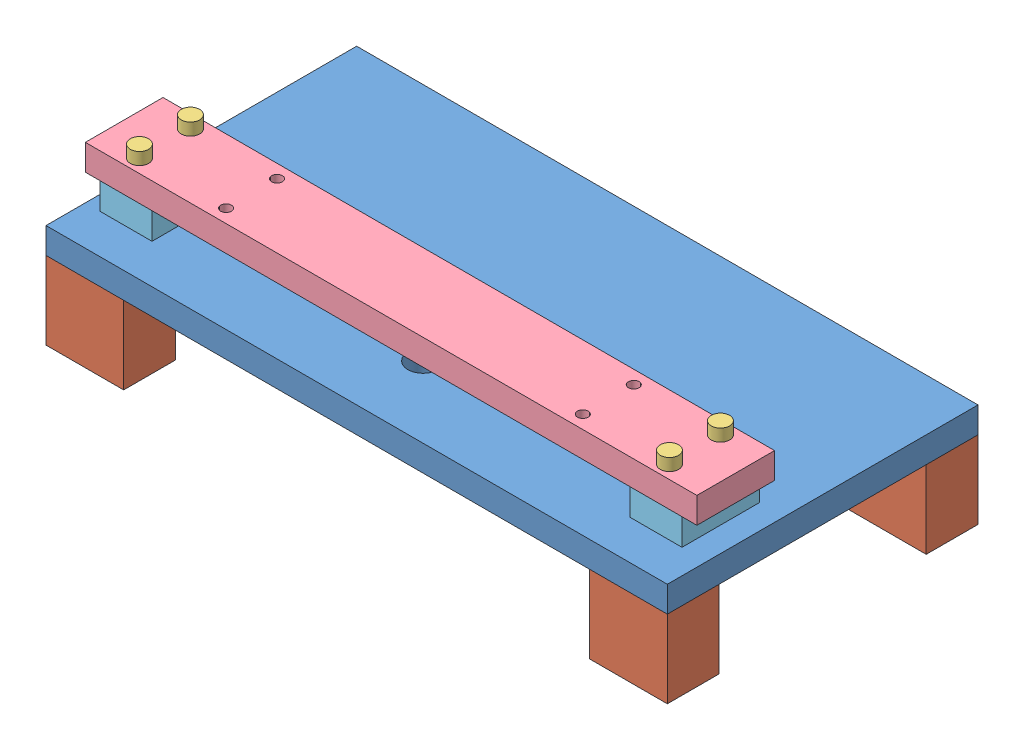
SolidWorks assembly 17model, configuration Default. Lengths in mm.
Overall size (609.6 165 304.8).
13 component instances, 5 part files, 17 mates.
Components (placement in the parent):
- 55model-1: 55model [Default] at (29.3323 -1.76 -14.2825) size (609.6 101.6 304.8)
  - Baseplate-1: Baseplate [Default] at (-329.9128 -7.7411 162.2827) size (609.6 25.4 304.8)
  - LongSpacer-1: LongSpacer [Default] at (-329.9128 -83.9411 162.2827) size (76.2 76.2 50.8)
  - LongSpacer-2: LongSpacer [Default] at (203.4872 -83.9411 162.2827) size (76.2 76.2 50.8)
  - LongSpacer-3: LongSpacer [Default] at (203.4872 -83.9411 -91.7173) size (76.2 76.2 50.8)
  - LongSpacer-4: LongSpacer [Default] at (-329.9128 -83.9411 -91.7173) size (76.2 76.2 50.8)
- LongScrew-1: LongScrew [Default] at (259.4195 79.2989 46.3001) x (-0.837169 0 -0.546944) z (-0.546944 0 0.837169) size (18 62 18)
- LongScrew-2: LongScrew [Default] at (-260.5805 79.2989 46.3001) x (-0.837169 0 -0.546944) z (-0.546944 0 0.837169) size (18 62 18)
- LongScrew-3: LongScrew [Default] at (259.4195 79.2989 96.3001) x (-0.837169 0 -0.546944) z (-0.546944 0 0.837169) size (18 62 18)
- LongScrew-4: LongScrew [Default] at (-260.5805 79.2989 96.3001) x (-0.837169 0 -0.546944) z (-0.546944 0 0.837169) size (18 62 18)
- 2-2model-1: 2-2model [Default] at (-300.5805 41.8989 109.4001) size (600 25.4 76.2)
- 49model-1: 49model [Default] at (259.4195 15.8989 71.3001) size (50.8 26 76.2)
- 49model-2: 49model [Default] at (-260.5805 15.8989 71.3001) size (50.8 26 76.2)
Mates (geometry in assembly coordinates):
- Concentric1: concentric aligned: circle of 2-2model-1; circle of 49model-2
- Concentric2: concentric aligned: circle of 2-2model-1; circle of 49model-2
- Coincident1: coincident anti-aligned: plane of 2-2model-1 through (-300.5805 41.8989 33.2001) normal (0 -1 0); plane of 49model-2 through (-235.1805 41.8989 33.2001) normal (0 1 0)
- Coincident2: coincident anti-aligned: plane of 2-2model-1 through (-300.5805 41.8989 33.2001) normal (0 -1 0); plane of 49model-1 through (284.8195 41.8989 33.2001) normal (0 1 0)
- Concentric3: concentric aligned: circle of 2-2model-1; circle of 49model-1
- Concentric4: concentric aligned: circle of 2-2model-1; circle of 49model-1
- Coincident3: coincident anti-aligned: plane of 2-2model-1 through (-300.5805 67.2989 33.2001) normal (0 1 0); plane of LongScrew-2 through (-260.5805 67.2989 46.3001) normal (0 -1 0)
- Coincident4: coincident anti-aligned: plane of 2-2model-1 through (-300.5805 67.2989 33.2001) normal (0 1 0); plane of LongScrew-4 through (-260.5805 67.2989 96.3001) normal (0 -1 0)
- Coincident5: coincident anti-aligned: plane of 2-2model-1 through (-300.5805 67.2989 33.2001) normal (0 1 0); plane of LongScrew-3 through (259.4195 67.2989 96.3001) normal (0 -1 0)
- Coincident6: coincident anti-aligned: plane of 2-2model-1 through (-300.5805 67.2989 33.2001) normal (0 1 0); plane of LongScrew-1 through (259.4195 67.2989 46.3001) normal (0 -1 0)
- Concentric6: concentric aligned: cylinder of LongScrew-2 through (-260.5805 17.2989 46.3001) axis (0 1 0) radius 6; cylinder of 2-2model-1 through (-260.5805 41.8989 46.3001) axis (0 1 0) radius 6.75
- Concentric7: concentric aligned: cylinder of LongScrew-4 through (-260.5805 17.2989 96.3001) axis (0 1 0) radius 6; circle of 2-2model-1
- Concentric8: concentric aligned: cylinder of LongScrew-3 through (259.4195 17.2989 96.3001) axis (0 1 0) radius 6; circle of 2-2model-1
- Concentric9: concentric aligned: cylinder of LongScrew-1 through (259.4195 17.2989 46.3001) axis (0 1 0) radius 6; cylinder of 2-2model-1 through (259.4195 41.8989 46.3001) axis (0 1 0) radius 6.75
- Coincident7: coincident aligned: plane of 55model-1/Baseplate-1 through (-300.5805 15.8989 148.0001) normal (-1 0 0); plane of 2-2model-1 through (-300.5805 67.2989 109.4001) normal (-1 0 0)
- Distance1: distance = 38.6 mm aligned: plane of 2-2model-1 through (-300.5805 67.2989 109.4001) normal (0 0 1); plane of 55model-1/Baseplate-1 through (-300.5805 15.8989 148.0001) normal (0 0 1)
- Coincident10: coincident anti-aligned: plane of 55model-1/Baseplate-1 through (-300.5805 15.8989 -156.7999) normal (0 1 0); plane of 49model-2 through (-235.1805 15.8989 33.2001) normal (0 -1 0)
